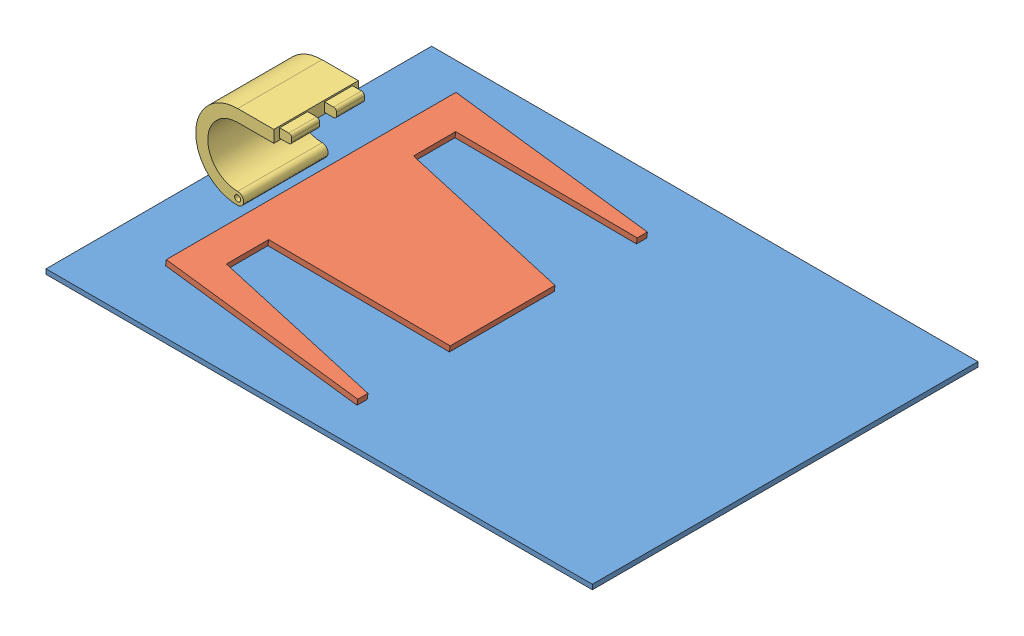
SolidWorks assembly TEST ASSEMBLY, CHARGING STATION, configuration Default. Lengths in mm.
Overall size (287.48 52.98 202.9).
3 component instances, 3 part files, 2 mates.
Components (placement in the parent):
- Ground-1: Ground [Default] at (-48.6697 5.4718 21.6175) size (287.48 2.54 202.9)
- RAMP, CHARGING STATION-1: RAMP, CHARGING STATION [Default] at (-70.3974 15.2107 12.6372) x (0.991445 -0.130526 0) z (0 0 1) size (101.6 3 152.4)
- ARM, CHARGING CONTACTS-1: ARM, CHARGING CONTACTS [Default] at (-136.827 17.5049 12.6372) size (47.46 44.12 44.45)
Mates (geometry in assembly coordinates):
- Angle1: planar angle = 0.1309 rad anti-aligned: plane of Ground-1 through (-164.628 8.0118 -95.0109) normal (0 1 0); plane of RAMP, CHARGING STATION-1 through (-20.032 8.5799 -63.5628) normal (-0.130526 -0.991445 0)
- Coincident2: coincident aligned: plane of RAMP, CHARGING STATION-1 through (-70.3974 15.2107 12.6372) normal (0 0 1); plane of ARM, CHARGING CONTACTS-1 through (-136.827 17.5049 12.6372) normal (0 0 1)
